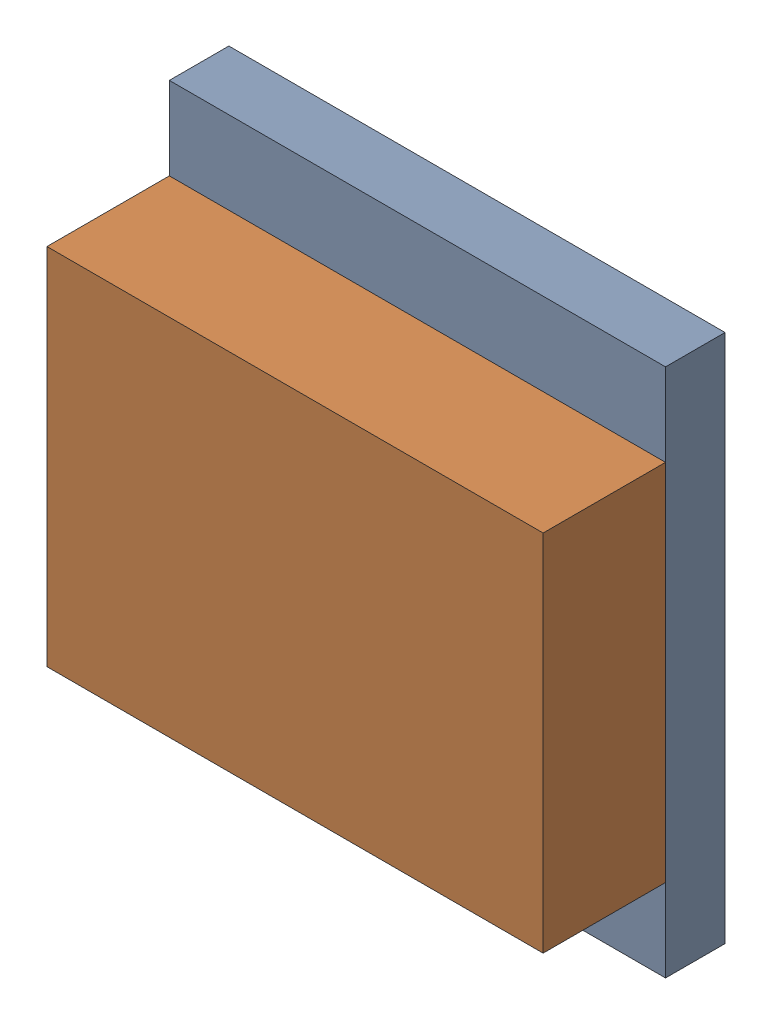
SolidWorks assembly LED5.step, configuration Default. Lengths in mm.
Overall size (1.5 1.6 0.55).
8 component instances, 4 part files, 0 mates.
Components (placement in the parent):
- 6440848816.step-1: 6440848816.step [Default] at (33.0608 -11.4554 0) size (1.5 1.6 0.18)
  - Extruded (10).step-1: Extruded (10).step [Default] at origin size (1.5 1.6 0.18)
- 6440848656.step-1: 6440848656.step [Default] at (33.0608 -11.4554 0.18) size (1.5 1.1 0.37)
  - Extruded (11).step-1: Extruded (11).step [Default] at origin size (1.5 1.1 0.37)
- 6440848496.step-1: 6440848496.step [Default] at (33.4358 -11.4556 0.18) size (0.3 0.3 0.18)
  - Extruded (12).step-1: Extruded (12).step [Default] at origin size (0.3 0.3 0.18)
- 6440848336.step-1: 6440848336.step [Default] at (32.6758 -11.4556 0.18) size (0.3 0.3 0.18)
  - Extruded (13).step-1: Extruded (13).step [Default] at origin size (0.3 0.3 0.18)
